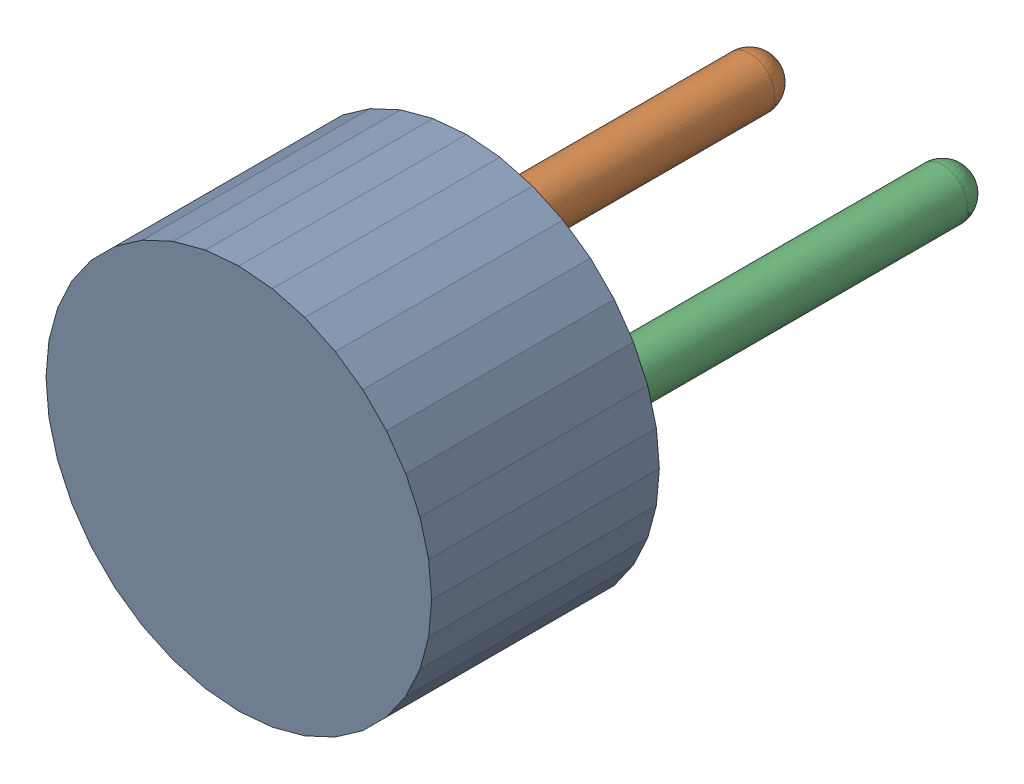
SolidWorks assembly C3, configuration Défaut. Lengths in mm.
Overall size (5.08 5.08 8.33).
4 component instances, 3 part files, 0 mates.
Components (placement in the parent):
- Open CASCADE STEP translator 6.8 1.19.1-1: Open CASCADE STEP translator 6.8 1.19.1 [Défaut] at origin size (5.08 5.08 8.33)
  - Body_1_10-1: Body_1_10 [Défaut] at origin size (5.08 5.08 3)
  - Pin_1_7-1: Pin_1_7 [Défaut] x (0 -1 0) z (0 0 1) size (0.66 0.66 7.16)
  - Pin_2_7-1: Pin_2_7 [Défaut] at (2.54 2.54 0) x (0 -1 0) z (0 0 1) size (0.66 0.66 7.16)
